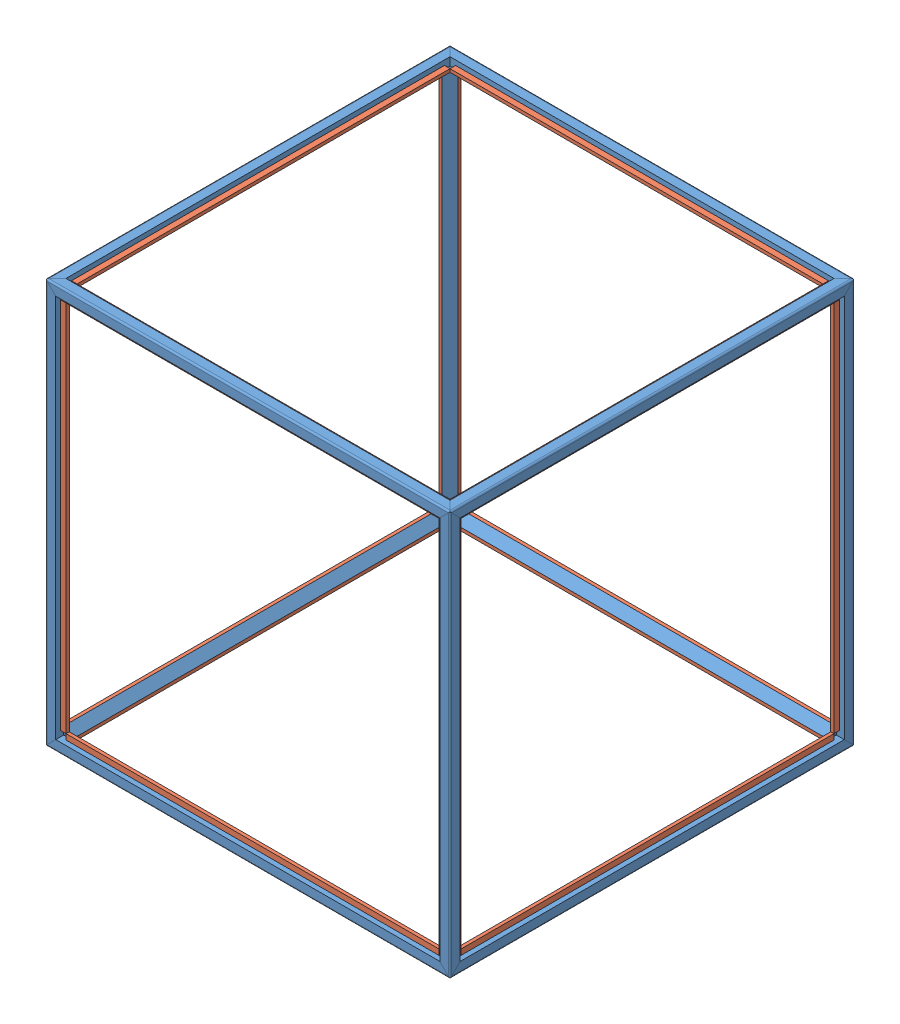
SolidWorks assembly Cube 2, configuration Default. Lengths in mm.
Overall size (729.34 729.34 348.28).
37 component instances, 3 part files, 1 mates.
Components (placement in the parent):
- Core Part-1: Core Part [Default] at origin size (301.14 301.14 301.14)
- Joiner-1: Joiner [Default] at origin size (301.14 301.14 301.14)
- Joiner-2: Joiner [Default] x (1 0 0) z (0 -1 0) size (301.14 301.14 301.14)
- Joiner-3: Joiner [Default] x (1 0 0) z (0 0 -1) size (301.14 301.14 301.14)
- VHB-1: VHB [Default] at origin size (301.14 301.14 301.14)
- VHB-2: VHB [Default] at (237.6716 0 0) x (0 0 -1) z (1 0 0) size (301.14 301.14 301.14)
- VHB-3: VHB [Default] at (237.6716 0 0) x (0 1 0) z (1 0 0) size (301.14 301.14 301.14)
- VHB-4: VHB [Default] at (237.6716 0 0) x (0 0 1) z (1 0 0) size (301.14 301.14 301.14)
- VHB-5: VHB [Default] x (1 0 0) z (0 -1 0) size (301.14 301.14 301.14)
- VHB-6: VHB [Default] x (1 0 0) z (0 0 -1) size (301.14 301.14 301.14)
- VHB-7: VHB [Default] at (0 237.6716 0) x (0 0 -1) z (0 1 0) size (301.14 301.14 301.14)
- VHB-8: VHB [Default] at (-237.6716 0 0) x (0 0 -1) z (-1 0 0) size (301.14 301.14 301.14)
- VHB-9: VHB [Default] at (0 -237.6716 0) x (0 0 -1) z (0 -1 0) size (301.14 301.14 301.14)
- VHB-10: VHB [Default] x (0 1 0) z (0 0 1) size (301.14 301.14 301.14)
- VHB-11: VHB [Default] x (-1 0 0) z (0 0 1) size (301.14 301.14 301.14)
- VHB-12: VHB [Default] x (0 -1 0) z (0 0 1) size (301.14 301.14 301.14)
- Joiner-4: Joiner [Default] x (0 1 0) z (0 0 1) size (301.14 301.14 301.14)
- Joiner-5: Joiner [Default] x (-1 0 0) z (0 0 1) size (301.14 301.14 301.14)
- Joiner-6: Joiner [Default] x (0 -1 0) z (0 0 1) size (301.14 301.14 301.14)
- Joiner-7: Joiner [Default] x (0 1 0) z (1 0 0) size (301.14 301.14 301.14)
- Joiner-8: Joiner [Default] x (-1 0 0) z (0 1 0) size (301.14 301.14 301.14)
- Joiner-9: Joiner [Default] x (0 -1 0) z (-1 0 0) size (301.14 301.14 301.14)
- Joiner-10: Joiner [Default] x (0 1 0) z (0 0 -1) size (301.14 301.14 301.14)
- Joiner-11: Joiner [Default] x (-1 0 0) z (0 0 -1) size (301.14 301.14 301.14)
- Joiner-12: Joiner [Default] x (0 -1 0) z (0 0 -1) size (301.14 301.14 301.14)
- VHB-13: VHB [Default] at (0 237.6716 0) x (-1 0 0) z (0 1 0) size (301.14 301.14 301.14)
- VHB-14: VHB [Default] at (-237.6716 0 0) x (0 -1 0) z (-1 0 0) size (301.14 301.14 301.14)
- VHB-15: VHB [Default] at (0 -237.6716 0) x (1 0 0) z (0 -1 0) size (301.14 301.14 301.14)
- VHB-16: VHB [Default] at (0 237.6716 0) x (0 0 1) z (0 1 0) size (301.14 301.14 301.14)
- VHB-17: VHB [Default] at (-237.6716 0 0) x (0 0 1) z (-1 0 0) size (301.14 301.14 301.14)
- VHB-18: VHB [Default] at (0 -237.6716 0) x (0 0 1) z (0 -1 0) size (301.14 301.14 301.14)
- VHB-19: VHB [Default] x (0 1 0) z (1 0 0) size (301.14 301.14 301.14)
- VHB-20: VHB [Default] x (-1 0 0) z (0 1 0) size (301.14 301.14 301.14)
- VHB-21: VHB [Default] x (0 -1 0) z (-1 0 0) size (301.14 301.14 301.14)
- VHB-22: VHB [Default] x (0 1 0) z (0 0 -1) size (301.14 301.14 301.14)
- VHB-23: VHB [Default] x (-1 0 0) z (0 0 -1) size (301.14 301.14 301.14)
- VHB-24: VHB [Default] x (0 -1 0) z (0 0 -1) size (301.14 301.14 301.14)
Mates (geometry in assembly coordinates):
- Coincident1: coordinate: unknown of Core Part-1
